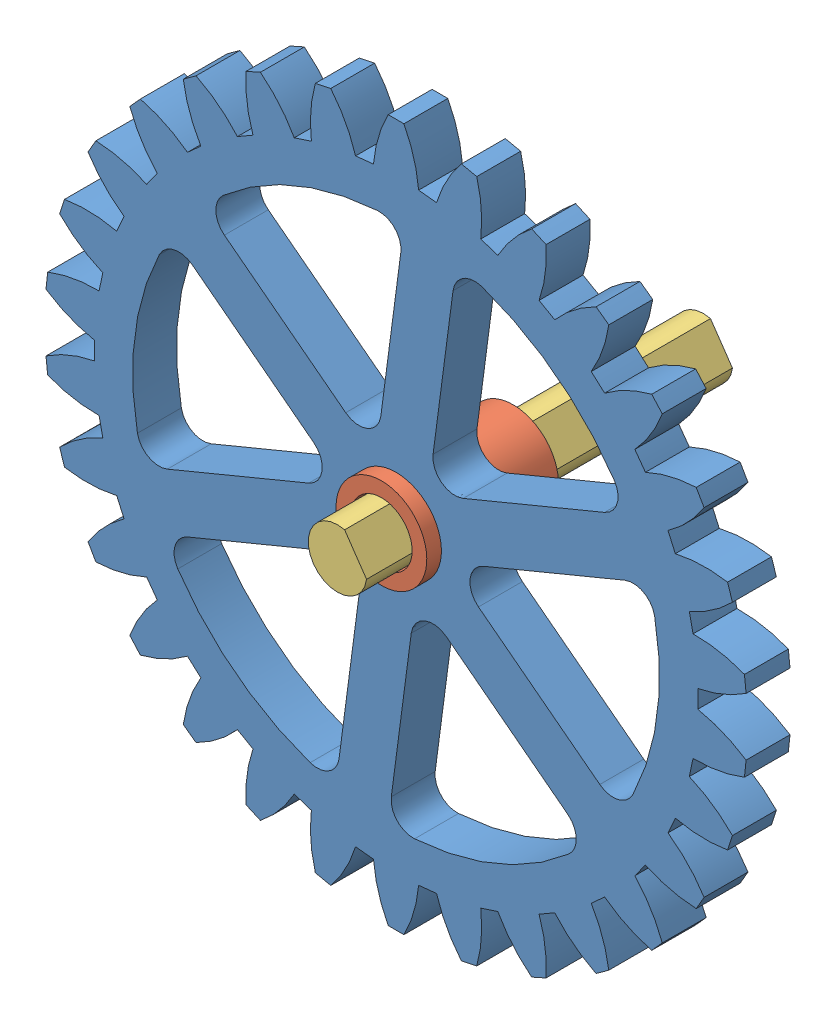
SolidWorks assembly SubAsmNum3, configuration Default. Lengths in mm.
Overall size (47.84 48 25).
4 component instances, 3 part files, 7 mates.
Components (placement in the parent):
- root_gear.-1: root_gear. [30T 1.5 Mod] at (23.2005 24.9477 32.625) size (47.84 48 3)
- GearboxSpacer-1: GearboxSpacer [4.2 ID 1mm] at (23.2005 24.9477 36.625) x (-0.966667 -0.256037 0) z (0 0 -1) size (6.2 6.2 1)
- GearboxSpacer-2: GearboxSpacer [4.2mm ID] at (23.2005 24.9477 27.625) x (-0.108036 0.994147 0) z (0 0 1) size (6.2 6.2 5)
- GearboxAxle-2: GearboxAxle [25mm] at (23.2005 24.9477 14.625) x (0.926974 -0.375125 0) z (0 0 1) size (4 3.98 25)
Mates (geometry in assembly coordinates):
- Coincident2: coincident anti-aligned: plane of root_gear.-1 through (23.2005 24.9477 35.625) normal (0 0 1); plane of GearboxSpacer-1 through (23.2005 24.9477 35.625) normal (0 0 -1)
- Coincident3: coincident anti-aligned: plane of root_gear.-1 through (23.2005 24.9477 32.625) normal (0 0 -1); plane of GearboxSpacer-2 through (23.2005 24.9477 32.625) normal (0 0 1)
- Concentric4: concentric anti-aligned: cylinder of root_gear.-1 through (23.2005 24.9477 32.625) axis (0 0 1) radius 2; cylinder of GearboxAxle-2 through (23.2005 24.9477 39.625) axis (0 0 -1) radius 2
- Coincident5: coincident anti-aligned: plane of root_gear.-1 through (25.1861 24.708 32.625) normal (-0.823876 -0.56677 0); plane of GearboxAxle-2 through (23.6866 26.8878 39.625) normal (0.823876 0.56677 0)
- Concentric5: concentric anti-aligned: cylinder of GearboxSpacer-1 through (23.2005 24.9477 35.625) axis (0 0 1) radius 2.1; cylinder of GearboxAxle-2 through (23.2005 24.9477 39.625) axis (0 0 -1) radius 2
- Concentric6: concentric aligned: cylinder of GearboxSpacer-2 through (23.2005 24.9477 32.625) axis (0 0 -1) radius 2.1; cylinder of GearboxAxle-2 through (23.2005 24.9477 39.625) axis (0 0 -1) radius 2
- Distance2: distance = 3 mm aligned: plane of GearboxAxle-2 through (23.2005 24.9477 39.625) normal (0 0 1); plane of GearboxSpacer-1 through (23.2005 24.9477 36.625) normal (0 0 1)
